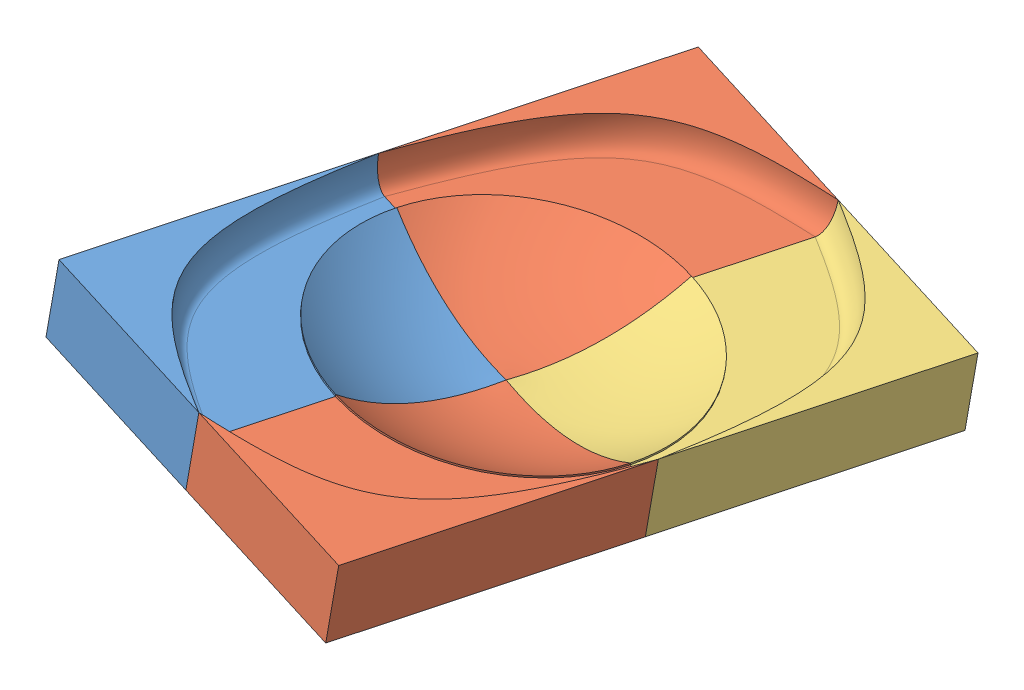
SolidWorks assembly full_transdec_2, configuration Default. Lengths in mm.
Overall size (80539.51 27013.75 103891.73).
4 component instances, 3 part files, 0 mates.
Components (placement in the parent):
- transdec_corner-1: transdec_corner [Default] at (-75161.8257 3343.1101 99939.7097) x (-0.969161 0.144842 -0.199368) z (-0.15292 -0.987906 0.025651) size (33813.99 49053.99 12968.95)
- Mirrortransdec_corner-4: Mirrortransdec_corner [Default] at (-45621.7961 -1071.6769 106016.4443) x (0.969161 -0.144842 0.199368) z (0.15292 0.987906 -0.025651) size (33813.99 49053.99 12968.95)
- Mirrortransdec_corner-7: Mirrortransdec_corner [Default] at (-66326.8343 812.6098 55152.9048) x (-0.969161 0.144842 -0.199368) z (0.15292 0.987906 -0.025651) size (33813.99 49053.99 12968.95)
- MirrorMirrortransdec_corner-8: MirrorMirrortransdec_corner [Default] at (-36786.8046 -3602.1772 61229.6394) x (0.969161 -0.144842 0.199368) z (-0.15292 -0.987906 0.025651) size (33813.99 49053.99 12968.95)
